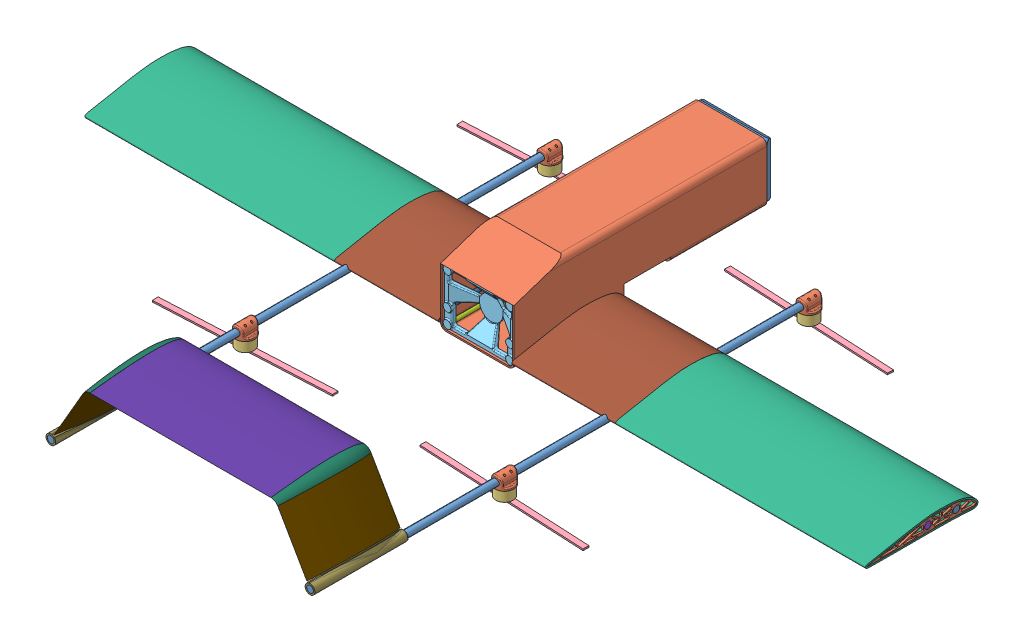
SolidWorks assembly jaguar, configuration Default. Lengths in mm.
Overall size (2540 278.31 1811.04).
84 component instances, 39 part files, 126 mates.
Components (placement in the parent):
- frontWingSpar-2: frontWingSpar [Default] at (-914.4 216.1264 -529.0897) size (711.2 21.59 21.59)
- frontWingSpar-3: frontWingSpar [Default] at (914.4 216.1264 -529.0897) size (711.2 21.59 21.59)
- simpleRib-1: simpleRib [Default] at (-1263.65 200.0443 -594.3259) x (0 0 1) z (-1 0 0) size (368.29 44.17 6.35)
- simpleRib-2: simpleRib [Default] at (-1060.45 200.0443 -594.3259) x (0 0 1) z (-1 0 0) size (368.29 44.17 6.35) (hidden)
- simpleRib-3: simpleRib [Default] at (-857.25 200.0443 -594.3259) x (0 0 1) z (-1 0 0) size (368.29 44.17 6.35)
- simpleRib-4: simpleRib [Default] at (-654.05 200.0443 -594.3259) x (0 0 1) z (-1 0 0) size (368.29 44.17 6.35)
- servoRib-1: servoRib [Default] at (-1060.45 200.0443 -594.3259) x (0 0 1) z (-1 0 0) size (356.03 44.17 6.35)
- simpleRib-5: simpleRib [Default] at (660.4 200.0443 -594.3259) x (0 0 1) z (-1 0 0) size (368.29 44.17 6.35)
- simpleRib-6: simpleRib [Default] at (863.6 200.0443 -594.3259) x (0 0 1) z (-1 0 0) size (368.29 44.17 6.35)
- servoRib-2: servoRib [Default] at (1066.8 200.0443 -594.3259) x (0 0 1) z (-1 0 0) size (356.03 44.17 6.35)
- simpleRib-7: simpleRib [Default] at (1270 200.0443 -594.3259) x (0 0 1) z (-1 0 0) size (368.29 44.17 6.35)
- rootRibLeft-1: rootRibLeft [Default] at (-457.2 200.0443 -594.3259) x (0 0 1) z (-1 0 0) size (366.68 65.15 24.26)
- rootRibRight-1: rootRibRight [Default] at (463.55 200.0443 -594.3259) x (0 0 1) z (-1 0 0) size (364.7 59.5 21.66)
- wingCover-1: wingCover [Default] at (1270 200.0443 -594.3259) x (0 0 1) z (-1 0 0) size (371.11 54.06 812.8)
- wingCover-2: wingCover [Default] at (-457.2 200.0443 -594.3259) x (0 0 1) z (-1 0 0) size (371.11 54.06 812.8)
- bodyRootRight-1: bodyRootRight [Default] at (457.2 200.0443 -594.3259) x (0 0 1) z (-1 0 0) size (366.68 65.15 24.26)
- fullSpar-1: fullSpar [Default] at (711.2 217.2724 -436.6337) size (1117.6 21.59 21.59)
- fullSpar-2: fullSpar [Default] at (-711.2 217.2724 -436.6337) size (1117.6 21.59 21.59)
- fullSpar-3: fullSpar [Default] at (0 216.1264 -529.0897) size (1117.6 21.59 21.59)
- frontSparBodyRib-1: frontSparBodyRib [Default] at (0 295.2474 -540.1387) x (-1 0 0) z (0 0 -1) size (228.6 228.6 44.96)
- midLinkSpar-1: midLinkSpar [Default] at (0 217.2724 -436.6337) size (304.8 21.59 21.59)
- bodyRootLeft-1: bodyRootLeft [Default] at (-450.85 200.0443 -594.3259) x (0 0 1) z (-1 0 0) size (362.2 55.58 16.67)
- simpleBodyRib-1: simpleBodyRib [Default] at (0 295.2474 -762.3887) size (228.6 181.1 6.35)
- VTOLSparLink-1: VTOLSparLink [Default] at (421.64 216.6994 -482.8617) x (-1 0 0) z (0 0 -1) size (53.63 58.17 126.91)
- VTOLSparLink-2: VTOLSparLink [Default] at (-421.64 216.6994 -482.8617) x (-1 0 0) z (0 0 -1) size (53.63 58.17 126.91)
- simpleRib-8: simpleRib [Default] at (396.24 200.0443 -594.3259) x (0 0 1) z (-1 0 0) size (368.29 44.17 6.35)
- simpleRib-9: simpleRib [Default] at (-389.89 200.0443 -594.3259) x (0 0 1) z (-1 0 0) size (368.29 44.17 6.35)
- servoRib-3: servoRib [Default] at (-186.69 200.0443 -594.3259) x (0 0 1) z (-1 0 0) size (356.03 44.17 6.35)
- servoRib-4: servoRib [Default] at (193.04 200.0443 -594.3259) x (0 0 1) z (-1 0 0) size (356.03 44.17 6.35)
- assembly-1: assembly [Default] at (13.3077 264.6671 -669.4387) size (228.6 190.88 177.8)
  - cameraBracket-1: cameraBracket [Default] at origin size (34.01 49 55)
  - motor-1: motor [Default] at (15.3923 -20.5 15) x (1 0 0) z (0 -0.863303 0.504685) size (14.3 34.5 34.5)
  - panBracket-1: panBracket [Default] at (29.6923 -20.5 15) size (90.84 83.7 83.67)
  - motor-2: motor [Default] at (-13.3077 45.5 15) x (0 1 0) z (0 0 1) size (14.3 34.5 34.5)
  - slipRingMount-1: slipRingMount [Default] at (-13.3077 59.8 15) size (44 18 44)
  - vibrationDampenerRing-1: vibrationDampenerRing [Default] at (-13.3077 55.5 15) size (119.3 20.84 106.17) (hidden)
  - jaguarCameraBracket-1: jaguarCameraBracket [Default] at (-13.3077 106.7803 15) size (228.6 47.08 177.8)
- VTOLSpar-1: VTOLSpar [Default] at (421.64 194.0284 -100.4647) x (0.999978 0.006602 0) z (0 0 1) size (22.1 22.1 1651)
- VTOLSpar-2: VTOLSpar [Default] at (-421.64 194.0284 -100.4647) x (-0.999978 0.006602 0) z (0 0 -1) size (22.1 22.1 1651)
- VTOLMotorMount-1: VTOLMotorMount [Default] at (421.64 193.6474 -898.0735) size (60 38.1 60)
- VTOLMotor-1: VTOLMotor [Default] at (421.64 174.5974 -898.0735) x (-0.889633 0 -0.456677) z (-0.456677 0 0.889633) size (56 36 56)
- VTOLMotor-3: VTOLMotor [Default] at (421.64 174.5974 92.5265) x (-0.889633 0 -0.456677) z (-0.456677 0 0.889633) size (56 36 56)
- VTOLMotorMount-4: VTOLMotorMount [Default] at (421.64 193.6474 92.5265) size (60 38.1 60)
- VTOLMotor-4: VTOLMotor [Default] at (-421.64 174.5974 -898.0735) x (0.889633 0 -0.456677) z (-0.456677 0 -0.889633) size (56 36 56)
- VTOLMotorMount-5: VTOLMotorMount [Default] at (-421.64 193.6474 -898.0735) x (-1 0 0) z (0 0 -1) size (60 38.1 60)
- VTOLMotor-5: VTOLMotor [Default] at (-421.64 174.5974 92.5265) x (0.889633 0 -0.456677) z (-0.456677 0 -0.889633) size (56 36 56)
- VTOLMotorMount-6: VTOLMotorMount [Default] at (-421.64 193.6474 92.5265) x (-1 0 0) z (0 0 -1) size (60 38.1 60)
- 22propeller-1: 22propeller [Default] at (421.64 137.0974 -898.0735) x (0.998774 0 0.049496) z (-0.049496 0 0.998774) size (558.8 5 19.05)
- 22propeller-2: 22propeller [Default] at (421.64 137.0974 92.5265) x (0.998774 0 0.049496) z (-0.049496 0 0.998774) size (558.8 5 19.05)
- 22propeller-3: 22propeller [Default] at (-421.64 137.0974 -898.0735) x (-0.998774 0 0.049496) z (-0.049496 0 -0.998774) size (558.8 5 19.05)
- 22propeller-4: 22propeller [Default] at (-421.64 137.0974 92.5265) x (-0.998774 0 0.049496) z (-0.049496 0 -0.998774) size (558.8 5 19.05)
- motorMount-1: motorMount [Default] at (0 269.7234 -247.7847) x (-1 0 0) z (0 0 -1) size (229.33 178.61 55.87)
- rearSparBodyRib-1: rearSparBodyRib [Default] at (0 295.1234 -425.5847) size (228.6 228.6 44.96)
- motorBodySparBottom-1: motorBodySparBottom [Default] at (101.6 193.5234 -400.1847) size (12.7 12.7 292.1)
- motorBodySparBottom-3: motorBodySparBottom [Default] at (-101.6 193.5234 -400.1847) size (12.7 12.7 292.1)
- motorBodySparTop-1: motorBodySparTop [Default] at (101.6 345.9234 -336.6847) size (12.7 12.7 165.1)
- motorBodySparTop-2: motorBodySparTop [Default] at (-101.6 345.9234 -336.6847) size (12.7 12.7 165.1)
- topBodySpar-1: topBodySpar [Default] at (101.6 396.7234 -743.0847) size (12.7 12.7 647.7)
- topBodySpar-2: topBodySpar [Default] at (-101.6 396.7234 -743.0847) x (-1 0 0) z (0 0 -1) size (12.7 12.7 647.7)
- midBodySpar-1: midBodySpar [Default] at (101.6 241.0214 -660.5347) size (12.7 12.7 812.8)
- midBodySpar-2: midBodySpar [Default] at (-101.6 241.0214 -660.5347) x (-1 0 0) z (0 0 -1) size (12.7 12.7 812.8)
- shorterWingCover-1: shorterWingCover [Default] at (457.2 200.0443 -594.3259) x (0 0 1) z (-1 0 0) size (371.11 54.06 337.82)
- shorterWingCover-2: shorterWingCover [Default] at (-119.38 200.0443 -594.3259) x (0 0 1) z (-1 0 0) size (371.11 54.06 337.82)
- sparMount-1: sparMount [Default] at (421.64 194.0284 572.6353) x (0.866025 0.5 0) z (0 0 1) size (34.87 36.2 304.8)
- sparMount-2: sparMount [Default] at (-421.5516 193.9774 572.6353) x (0.866025 -0.5 0) z (0 0 1) size (34.87 36.2 304.8)
- tailSpar_skewer-1: tailSpar_skewer [Default] at (370.0145 283.4464 490.0853) x (0.85828 0.495528 -0.133447) z (0.5 -0.866025 0) size (6.35 6.35 228.6)
- tailSpar_skewer-2: tailSpar_skewer [Default] at (370.0145 283.4464 604.3853) x (0.85828 0.495528 -0.133447) z (0.5 -0.866025 0) size (6.35 6.35 228.6)
- tailSpar_skewer-3: tailSpar_skewer [Default] at (-370.0145 283.4464 490.0853) x (-0.85828 0.495528 -0.133447) z (0.5 0.866025 0) size (6.35 6.35 228.6)
- tailSpar_skewer-4: tailSpar_skewer [Default] at (-370.0145 283.4464 604.3853) x (-0.85828 0.495528 -0.133447) z (0.5 0.866025 0) size (6.35 6.35 228.6)
- tailRib-1: tailRib [Default] at (362.585 296.3147 572.6353) x (0.866025 0.5 0) z (-0.5 0.866025 0) size (22.29 250.1 3.81)
- tailRib-2: tailRib [Default] at (-360.68 299.6142 572.6353) x (-0.866025 0.5 0) z (-0.5 -0.866025 0) size (22.29 250.1 3.81)
- tailTopAdapter-1: tailTopAdapter [Default] at (316.6745 375.834 572.6353) x (0.866025 0.5 0) z (-0.5 0.866025 0) size (37.33 302.14 43.33)
- horizontalTailSpar_skewer-1: horizontalTailSpar_skewer [Default] at (0.0375 388.534 490.0853) x (0 0 -1) z (1 0 0) size (6.35 6.35 614.68)
- horizontalTailSpar_skewer-2: horizontalTailSpar_skewer [Default] at (0.0375 388.534 604.3853) x (0 0 -1) z (1 0 0) size (6.35 6.35 614.68)
- tailTopAdapter-4: tailTopAdapter [Default] at (-294.6025 388.6185 572.6352) x (0 0.999999 -0.001024) z (-1 0 0) size (37.33 302.14 43.33)
- tailRib-3: tailRib [Default] at (-1.2325 388.534 572.6353) x (0 -1 0) z (1 0 0) size (22.29 250.1 3.81)
- tailRib-4: tailRib [Default] at (163.8675 388.534 572.6353) x (0 -1 0) z (1 0 0) size (22.29 250.1 3.81)
- tailRib-5: tailRib [Default] at (-166.3325 388.534 572.6353) x (0 -1 0) z (1 0 0) size (22.29 250.1 3.81)
- tailRib-6: tailRib [Default] at (-1.2325 388.534 572.6353) x (0 -1 0) z (1 0 0) size (22.29 250.1 3.81)
- tailTopCover-1: tailTopCover [Default] at (0.0375 388.534 572.6353) x (0 -1 0) z (1 0 0) size (32.84 302.14 589.28)
- tailSideCover-1: tailSideCover [Default] at (364.0455 293.785 572.6353) x (0.866025 0.5 0) z (-0.5 0.866025 0) size (32.84 302.14 189.74)
- tailSideCover-2: tailSideCover [Default] at (-364.0455 293.785 572.6353) x (-0.866025 0.5 0) z (-0.5 -0.866025 0) size (32.84 302.14 189.74)
- noseConeBodyRib-1: noseConeBodyRib [Default] at (0 295.1234 -1069.4747) size (228.6 181.1 22.86)
- frontBodyCover-1: frontBodyCover [Default] at (0 318.8724 -906.4067) size (238.76 238.76 822.96)
Mates (geometry in assembly coordinates):
- Distance3: distance = 1270 mm: plane of frontWingSpar-2 through (-1270 216.1264 -529.0897) normal (-1 0 0); plane of assembly through (0 0 0) normal (1 0 0)
- Distance4: distance = 2540 mm: plane of frontWingSpar-2 through (-1270 216.1264 -529.0897) normal (-1 0 0); plane of frontWingSpar-3 through (1270 216.1264 -529.0897) normal (1 0 0)
- Concentric1: concentric: circle of broomStick-2; circle of broomStick-3
- Concentric2: concentric: circle of broomStick-2; circle of simpleRib-1
- Coincident6: coincident: plane of frontWingSpar-2 through (-1270 216.1264 -529.0897) normal (-1 0 0); plane of simpleRib-1 through (-1270 206.3604 -592.3318) normal (-1 0 0)
- Distance2: distance = 203.2 mm aligned: plane of simpleRib-1 through (-1270 206.3604 -592.3318) normal (-1 0 0); plane of servoRib-1 through (-1066.8 206.3604 -592.3318) normal (-1 0 0)
- Concentric3: concentric: circle of simpleRib-1; circle of servoRib-1
- Concentric4: concentric: circle of broomStick-2; circle of servoRib-1
- Distance5: distance = 812.8 mm anti-aligned: plane of rootRibLeft-1 through (-457.2 206.3604 -592.3318) normal (1 0 0); plane of simpleRib-1 through (-1270 206.3604 -592.3318) normal (-1 0 0)
- Concentric5: concentric anti-aligned: circle of broomStick-2; circle of rootRibLeft-1
- Concentric6: concentric aligned: circle of simpleRib-4; circle of rootRibLeft-1
- Distance6: distance = 812.8 mm: plane of rootRibRight-1 through (457.2 206.3604 -592.3318) normal (-1 0 0); plane of simpleRib-7 through (1270 206.3604 -592.3318) normal (1 0 0)
- Concentric7: concentric: circle of broomStick-3; circle of rootRibRight-1
- Concentric8: concentric: circle of simpleRib-5; circle of rootRibRight-1
- Coincident12: coincident: plane of frontWingSpar-3 through (1270 216.1264 -529.0897) normal (1 0 0); plane of wingCover-1 through (1270 209.3297 -596.4536) normal (1 0 0)
- Concentric96: concentric: unknown of frontWingSpar-3; unknown of wingCover-1
- Concentric10: concentric: circle of simpleRib-7; circle of wingCover-1
- Coincident14: coincident aligned: plane of frontWingSpar-2 through (-1270 216.1264 -529.0897) normal (-1 0 0); plane of wingCover-2 through (-1270 209.3297 -596.4536) normal (-1 0 0)
- Concentric12: concentric aligned: circle of simpleRib-1; circle of wingCover-2
- Concentric13: concentric aligned: circle of rootRibLeft-1; circle of wingCover-2
- Coincident15: coincident: plane of rootRibRight-1 through (457.2 206.3604 -592.3318) normal (-1 0 0); plane of bodyRootRight-1 through (457.2 206.3604 -592.3318) normal (1 0 0)
- Concentric14: concentric: unknown of frontWingSpar-3; unknown of bodyRootRight-1
- Concentric15: concentric: unknown of simpleRib-7; unknown of bodyRootRight-1
- Coincident16: coincident: plane of frontWingSpar-3 through (1270 216.1264 -529.0897) normal (1 0 0); plane of fullSpar-1 through (1270 217.2724 -436.6337) normal (1 0 0)
- Concentric17: concentric: circle of simpleRib-7; circle of midSpar-1
- Coincident17: coincident: plane of frontWingSpar-2 through (-1270 216.1264 -529.0897) normal (-1 0 0); plane of fullSpar-2 through (-1270 217.2724 -436.6337) normal (-1 0 0)
- Concentric18: concentric: circle of simpleRib-1; circle of midSpar-2
- Concentric19: concentric: circle of shortSpar-2; circle of fullSpar-3
- Distance7: distance = 558.8 mm: plane of assembly through (0 0 0) normal (1 0 0); plane of fullSpar-3 through (558.8 216.1264 -529.0897) normal (1 0 0)
- Concentric20: concentric: circle of shortSpar-3; circle of frontSparBodyRib-1
- Distance9: distance = 1384.3 mm: plane of frontSparBodyRib-1 through (-114.3 193.6474 -552.8387) normal (-1 0 0); plane of frontWingSpar-3 through (1270 216.1264 -529.0897) normal (1 0 0)
- Coincident19: coincident anti-aligned: plane of fullSpar-1 through (152.4 217.2724 -436.6337) normal (-1 0 0); plane of midLinkSpar-1 through (152.4 217.2724 -436.6337) normal (1 0 0)
- Concentric22: concentric aligned: circle of fullSpar-1; circle of midLinkSpar-1
- Concentric23: concentric: unknown of simpleRib-7; unknown of rearSparBodyRib-1
- Coincident22: coincident: plane of frontSparBodyRib-1 through (114.3 193.6474 -552.8387) normal (1 0 0); plane of rearSparBodyRib-1 through (114.3 193.5234 -412.8847) normal (1 0 0)
- Coincident23: coincident anti-aligned: plane of rootRibLeft-1 through (-457.2 206.3604 -592.3318) normal (1 0 0); plane of bodyRootLeft-1 through (-457.2 206.3604 -592.3318) normal (-1 0 0)
- Concentric24: concentric: unknown of simpleRib-7; unknown of bodyRootLeft-1
- Concentric25: concentric: unknown of simpleRib-7; unknown of bodyRootLeft-1
- Distance10: distance = 203.2 mm anti-aligned: plane of frontSparBodyRib-1 through (-101.6 193.6474 -552.8387) normal (0 0 -1); plane of simpleBodyRib-1 through (101.6 396.8474 -756.0387) normal (0 0 1)
- Concentric27: concentric anti-aligned: circle of frontSparBodyRib-1; circle of simpleBodyRib-1
- Concentric28: concentric anti-aligned: unknown of simpleBodyRib-1; unknown of frontSparBodyRib-1
- Coincident27: coincident anti-aligned: plane of bodyRootLeft-1 through (-447.04 217.2724 -436.6337) normal (1 0 0); plane of VTOLSparLink-2 through (-447.04 217.2724 -436.6337) normal (-1 0 0)
- Concentric33: concentric anti-aligned: circle of bodyRootLeft-1; circle of VTOLSparLink-2
- Concentric34: concentric anti-aligned: circle of bodyRootLeft-1; circle of VTOLSparLink-2
- Coincident30: coincident anti-aligned: plane of bodyRootRight-1 through (447.04 217.2724 -436.6337) normal (-1 0 0); plane of VTOLSparLink-1 through (447.04 217.2724 -436.6337) normal (1 0 0)
- Concentric35: concentric aligned: circle of bodyRootRight-1; circle of VTOLSparLink-1
- Concentric36: concentric aligned: circle of bodyRootRight-1; circle of VTOLSparLink-1
- Coincident33: coincident anti-aligned: plane of VTOLSparLink-1 through (396.24 216.1264 -529.0897) normal (-1 0 0); plane of simpleRib-8 through (396.24 206.3604 -592.3318) normal (1 0 0)
- Concentric37: concentric: circle of simpleRib-8; circle of frontWingSpar-3
- Concentric38: concentric: circle of simpleRib-7; circle of simpleRib-8
- Coincident35: coincident: plane of VTOLSparLink-2 through (-396.24 216.1264 -529.0897) normal (1 0 0); plane of simpleRib-9 through (-396.24 206.3604 -592.3318) normal (-1 0 0)
- Concentric39: concentric: circle of frontWingSpar-2; circle of simpleRib-9
- Concentric40: concentric: circle of simpleRib-1; circle of simpleRib-9
- Distance11: distance = 203.2 mm aligned: plane of servoRib-3 through (-186.69 206.3604 -592.3318) normal (1 0 0); plane of simpleRib-9 through (-389.89 206.3604 -592.3318) normal (1 0 0)
- Concentric41: concentric: circle of frontWingSpar-2; circle of servoRib-3
- Concentric42: concentric: circle of simpleRib-1; circle of servoRib-3
- Distance12: distance = 203.2 mm aligned: plane of servoRib-4 through (186.69 206.3604 -592.3318) normal (-1 0 0); plane of simpleRib-8 through (389.89 206.3604 -592.3318) normal (-1 0 0)
- Concentric43: concentric: circle of frontWingSpar-3; circle of servoRib-4
- Concentric44: concentric: circle of fullSpar-1; circle of servoRib-4
- Distance13: distance = 12.7 mm anti-aligned: plane of assembly-1/jaguarCameraBracket-1 through (-101.6 396.8474 -565.5387) normal (0 0 1); plane of frontSparBodyRib-1 through (-101.6 193.6474 -552.8387) normal (0 0 -1)
- Concentric45: concentric anti-aligned: circle of frontSparBodyRib-1; circle of assembly-1/jaguarCameraBracket-1
- Concentric46: concentric anti-aligned: circle of frontSparBodyRib-1; circle of assembly-1/jaguarCameraBracket-1
- Concentric47: concentric: circle of VTOLSparLink-1; circle of VTOLSpar-1
- Distance14: distance = 381 mm aligned: plane of VTOLSpar-1 through (421.64 194.0284 -925.9647) normal (0 0 -1); plane of VTOLSparLink-1 through (421.64 194.0284 -544.9647) normal (0 0 -1)
- Tangent1: tangent: curve of VTOLSpar-1; edge_curve of VTOLMotorMount-1
- Parallel1: parallel: plane of VTOLMotorMount-1 through (421.64 174.5974 -898.0735) normal (0 -1 0); plane of assembly through (0 0 0) normal (0 1 0)
- Coincident39: coincident anti-aligned: plane of VTOLMotorMount-1 through (421.64 174.5974 -898.0735) normal (0 -1 0); plane of VTOLMotor-1 through (421.64 174.5974 -898.0735) normal (0 1 0)
- Concentric48: concentric anti-aligned: circle of VTOLMotorMount-1; circle of VTOLMotor-1
- Concentric49: concentric: circle of VTOLSpar-1; circle of VTOLMotorMount-1
- Concentric50: concentric aligned: circle of VTOLMotorMount-1; circle of VTOLMotorMount-3
- Coincident43: coincident anti-aligned: plane of VTOLMotor-1 through (421.64 142.0974 -898.0735) normal (0 -1 0); plane of 22propeller-1 through (421.64 142.0974 -898.0735) normal (0 1 0)
- Concentric51: concentric anti-aligned: circle of VTOLMotor-1; circle of 22propeller-1
- Distance15: distance = 152.4 mm: plane of rearSparBodyRib-1 through (101.6 193.5234 -412.8847) normal (0 0 1); plane of motorMount-1 through (-101.6 193.5234 -260.4847) normal (0 0 -1)
- Concentric52: concentric: unknown of motorMount-1; unknown of rearSparBodyRib-1
- Concentric53: concentric: unknown of motorMount-1; unknown of rearSparBodyRib-1
- Concentric54: concentric: circle of simpleRib-7; circle of rearSparBodyRib-1
- Concentric55: concentric: circle of motorMount-1; circle of rearSparBodyRib-1
- Concentric56: concentric: circle of motorMount-1; circle of rearSparBodyRib-1
- Coincident50: coincident anti-aligned: plane of motorMount-1 through (101.6 193.5234 -254.1347) normal (0 0 -1); plane of motorBodySparBottom-1 through (101.6 193.5234 -254.1347) normal (0 0 1)
- Concentric57: concentric anti-aligned: circle of motorMount-1; circle of motorBodySparBottom-1
- Coincident52: coincident anti-aligned: plane of motorMount-1 through (-101.6 193.5234 -254.1347) normal (0 0 -1); plane of motorBodySparBottom-3 through (-101.6 193.5234 -254.1347) normal (0 0 1)
- Concentric58: concentric anti-aligned: circle of motorMount-1; circle of motorBodySparBottom-3
- Coincident53: coincident anti-aligned: plane of motorMount-1 through (101.6 345.9234 -254.1347) normal (0 0 -1); plane of motorBodySparTop-1 through (101.6 345.9234 -254.1347) normal (0 0 1)
- Concentric59: concentric anti-aligned: circle of motorMount-1; circle of motorBodySparTop-1
- Coincident55: coincident anti-aligned: plane of motorMount-1 through (-101.6 345.9234 -254.1347) normal (0 0 -1); plane of motorBodySparTop-2 through (-101.6 345.9234 -254.1347) normal (0 0 1)
- Concentric60: concentric anti-aligned: circle of motorMount-1; circle of motorBodySparTop-2
- Parallel3: parallel: plane of motorMount-1 through (0 269.7234 -285.8847) normal (0 0 1); plane of rearSparBodyRib-1 through (-101.6 396.7234 -423.0447) normal (0 0 1)
- Parallel4: parallel: plane of frontSparBodyRib-1 through (-101.6 193.6474 -540.1387) normal (0 0 1); plane of rearSparBodyRib-1 through (-101.6 396.7234 -423.0447) normal (0 0 1)
- Parallel5: parallel aligned: plane of frontSparBodyRib-1 through (-101.6 193.6474 -540.1387) normal (0 0 1); plane of simpleBodyRib-1 through (-101.6 396.8474 -761.1187) normal (0 0 1)
- Coincident61: coincident: circle of rearSparBodyRib-1; plane of topBodySpar-1 through (101.6 396.7234 -419.2347) normal (0 0 1)
- Concentric62: concentric: circle of rearSparBodyRib-1; circle of topBodySpar-1
- Coincident63: coincident anti-aligned: plane of motorMount-1 through (101.6 241.0214 -254.1347) normal (0 0 -1); plane of midBodySpar-1 through (101.6 241.0214 -254.1347) normal (0 0 1)
- Concentric63: concentric anti-aligned: circle of motorMount-1; circle of midBodySpar-1
- Coincident65: coincident: plane of wingCover-1 through (457.2 209.3297 -596.4536) normal (-1 0 0); plane of shorterWingCover-1 through (457.2 209.3297 -596.4536) normal (1 0 0)
- Concentric64: concentric: circle of frontWingSpar-3; circle of shorterWingCover-1
- Concentric65: concentric: circle of simpleRib-7; circle of shorterWingCover-1
- Concentric66: concentric aligned: circle of VTOLSpar-1; circle of sparMount-1
- Coincident68: coincident: plane of VTOLSpar-1 through (421.64 194.0284 725.0353) normal (0 0 1); plane of sparMount-1 through (421.64 194.0284 725.0353) normal (0 0 1)
- Angle1: planar angle = 0.523599 rad: line of sparMount-1 through (413.7025 207.7766 681.7606) axis (-0.5 0.866025 0); line of motorMount-1 through (-114.3 251.5709 -247.7847) axis (0 1 0)
- Tangent2: tangent: cylinder of VTOLSpar-1 through (421.64 194.0284 725.0353) axis (0 0 -1) radius 11.049; plane of tailSpar_skewer-1 through (427.1645 184.4597 490.0853) normal (0.5 -0.866025 0)
- Concentric67: concentric: circle of sparMount-1; circle of tailSpar_skewer-1
- Concentric68: concentric: circle of tailSpar_skewer-1; circle of tailRib-1
- Concentric69: concentric: circle of tailSpar_skewer-2; circle of tailRib-1
- Distance16: distance = 101.6 mm: plane of tailRib-1 through (351.3318 294.217 520.8736) normal (-0.5 0.866025 0); plane of sparMount-1 through (402.1318 206.2288 520.8736) normal (-0.5 0.866025 0)
- Coincident69: coincident: plane of tailSpar_skewer-1 through (312.8645 382.4331 490.0853) normal (-0.5 0.866025 0); plane of tailTopAdapter-1 through (312.8645 382.4331 490.0853) normal (0.5 -0.866025 0)
- Concentric70: concentric: circle of tailSpar_skewer-1; circle of tailTopAdapter-1
- Concentric71: concentric: circle of tailSpar_skewer-2; circle of tailTopAdapter-1
- Coincident83: coincident anti-aligned: plane of tailTopAdapter-1 through (307.3775 388.534 490.0853) normal (-1 0 0); plane of horizontalTailSpar_skewer-1 through (307.3775 388.534 490.0853) normal (1 0 0)
- Concentric80: concentric anti-aligned: circle of tailTopAdapter-1; circle of horizontalTailSpar_skewer-1
- Concentric86: concentric aligned: circle of horizontalTailSpar_skewer-1; circle of tailTopAdapter-4
- Distance17: distance = 589.28 mm anti-aligned: plane of tailTopAdapter-4 through (-294.6025 404.4255 527.5114) normal (1 0 0); plane of tailTopAdapter-1 through (294.6775 404.3871 527.5276) normal (-1 0 0)
- Distance18: distance = 292.1 mm: plane of tailTopAdapter-1 through (294.6775 404.3871 527.5276) normal (-1 0 0); plane of tailRib-3 through (2.5775 399.3284 520.8736) normal (1 0 0)
- Concentric87: concentric anti-aligned: cylinder of horizontalTailSpar_skewer-1 through (307.3775 388.534 490.0853) axis (-1 0 0) radius 3.175; circle of tailRib-3
- Concentric88: concentric: cylinder of horizontalTailSpar_skewer-2 through (307.3775 388.534 604.3853) axis (-1 0 0) radius 3.175; circle of tailRib-3
- Coincident84: coincident anti-aligned: plane of tailTopAdapter-4 through (-294.6025 404.4255 527.5114) normal (1 0 0); plane of tailTopCover-1 through (-294.6025 372.6808 527.5276) normal (-1 0 0)
- Concentric89: concentric anti-aligned: cylinder of horizontalTailSpar_skewer-1 through (307.3775 388.534 490.0853) axis (-1 0 0) radius 3.175; circle of tailTopCover-1
- Concentric90: concentric: cylinder of horizontalTailSpar_skewer-2 through (307.3775 388.534 604.3853) axis (-1 0 0) radius 3.175; circle of tailTopCover-1
- Coincident89: coincident anti-aligned: plane of sparMount-1 through (402.1318 206.2288 520.8736) normal (-0.5 0.866025 0); plane of tailSideCover-1 through (425.2092 219.5526 527.5276) normal (0.5 -0.866025 0)
- Concentric91: concentric: cylinder of tailSpar_skewer-1 through (427.1645 184.4597 490.0853) axis (-0.5 0.866025 0) radius 3.175; circle of tailSideCover-1
- Coincident91: coincident: cylinder of tailSpar_skewer-2 through (427.1645 184.4597 604.3853) axis (-0.5 0.866025 0) radius 3.175; circle of tailSideCover-1
- Coincident92: coincident anti-aligned: plane of topBodySpar-2 through (-101.6 396.7234 -1066.9347) normal (0 0 -1); plane of noseConeBodyRib-1 through (-101.6 396.7234 -1066.9347) normal (0 0 1)
- Concentric92: concentric: circle of topBodySpar-1; circle of noseConeBodyRib-1
- Concentric93: concentric: circle of topBodySpar-2; circle of noseConeBodyRib-1
- Coincident93: coincident anti-aligned: plane of noseConeBodyRib-1 through (101.6 396.7234 -1063.1247) normal (0 0 1); plane of frontBodyCover-1 through (101.6 241.0214 -1063.1247) normal (0 0 -1)
- Concentric94: concentric: cylinder of topBodySpar-1 through (101.6 396.7234 -419.2347) axis (0 0 -1) radius 6.35; circle of frontBodyCover-1
- Concentric95: concentric: cylinder of topBodySpar-2 through (-101.6 396.7234 -1066.9347) axis (0 0 1) radius 6.35; circle of frontBodyCover-1
